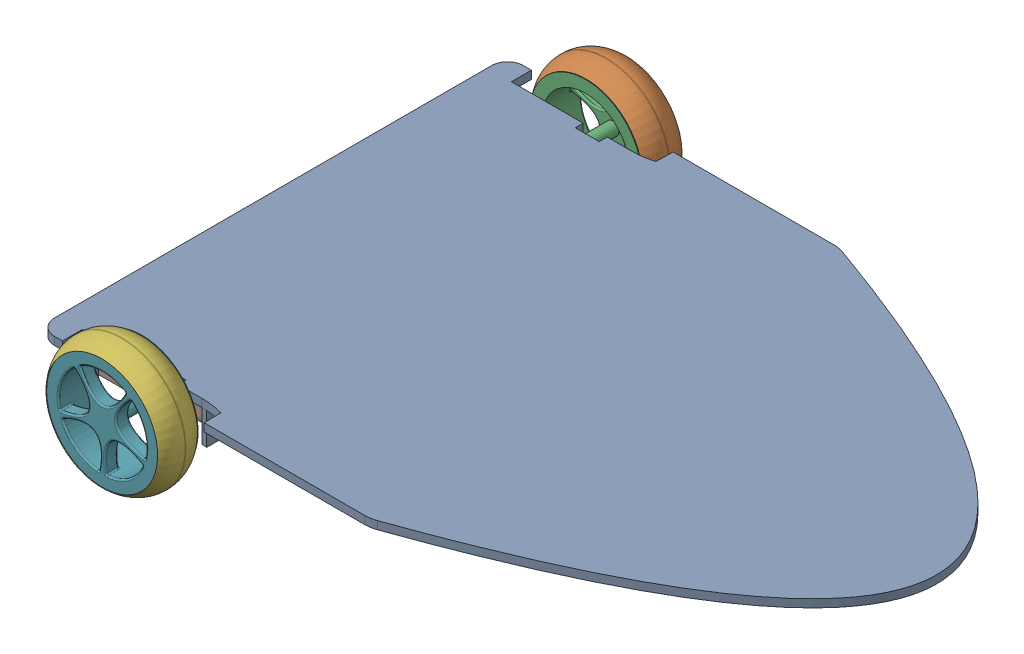
SolidWorks assembly Three_wheeled_base, configuration Predeterminado. Lengths in mm.
Overall size (832 160.33 657.43).
7 component instances, 5 part files, 12 mates.
Components (placement in the parent):
- Base-1: Base [Predeterminado] at (5.8411 10.0672 416) size (832 50 588)
- Rear_wheel-1: Rear_wheel [Predeterminado] at (-266.5903 -12.0958 99.7873) x (1 0 0) z (0 -1 0) size (160 66.79 160)
- Caster_coupler-1: Caster_coupler [Predeterminado] at (255.8411 5.8953 416) x (-1 0 0) z (0 0 1) size (37.38 89 35)
- Rear_coupler-1: Rear_coupler [Predeterminado] at (-286.1846 -2.1047 172.9246) x (1 0 0) z (0 0 -1) size (150 40 54)
- Rear_wheel-2: Rear_wheel [Predeterminado] at (-266.5903 -12.1135 732.213) x (1 0 0) z (0 1 0) size (160 66.79 160)
- Rear_coupler-2: Rear_coupler [Predeterminado] at (-286.1846 -22.1047 659.0757) size (150 40 54)
- Caster_wheel-2: Caster_wheel [Predeterminado] at (266.1413 -72.4241 416) x (1 0 0) z (0 -1 0) size (40 18 40)
Mates (geometry in assembly coordinates):
- Coincidente1: coincident anti-aligned: plane of Base-1 through (255.8411 3.8953 416) normal (0 1 0); plane of Caster_coupler-1 through (255.8411 3.8953 416) normal (0 -1 0)
- Concéntrica1: concentric aligned: circle of Base-1; circle of Caster_coupler-1
- Coincidente7: coincident anti-aligned: plane of Base-1 through (-200.5898 -32.1047 188.0801) normal (0 0 -1); plane of Coupler-1 through (-230.5898 -32.1047 188.0801) normal (0 0 1)
- Coincidente8: coincident anti-aligned: plane of Base-1 through (35.4102 7.8953 416.0001) normal (0 -1 0); plane of Coupler-1 through (-290.5898 7.8953 173.0801) normal (0 1 0)
- Coincidente9: coincident anti-aligned: plane of Base-1 through (-230.5898 7.8953 157.0601) normal (-1 0 0); plane of Coupler-1 through (-230.5898 -32.1047 158.0801) normal (1 0 0)
- Coincidente10: coincident anti-aligned: circle of Big_wheel-1; circle of Coupler-1
- Coincidente11: coincident anti-aligned: plane of Base-1 through (35.4102 7.8953 416.0001) normal (0 -1 0); plane of Coupler-2 through (-290.5898 7.8953 658.9201) normal (0 1 0)
- Coincidente12: coincident anti-aligned: plane of Base-1 through (-200.5898 -32.1047 643.9201) normal (0 0 1); plane of Coupler-2 through (-230.5898 7.8953 643.9201) normal (0 0 -1)
- Coincidente13: coincident anti-aligned: circle of Big_wheel-2; circle of Coupler-2
- Concéntrica2: concentric anti-aligned: cylinder of Caster_coupler-1 through (266.1413 -72.4241 398.5) axis (0 0 1) radius 2; axis of Small_wheel-2 through (266.1413 -72.4241 425) axis (0 0 -1)
- Distancia1: distance = 1 mm anti-aligned: plane of Small_wheel-2 through (266.1413 -72.4241 421) normal (0 0 1); plane of Caster_coupler-1 through (277.4494 -81.0324 422) normal (0 0 -1)
- Coincidente15: coincident anti-aligned: plane of Base-1 through (-230.5898 7.8953 674.9401) normal (-1 0 0); plane of Coupler-2 through (-230.5898 7.8953 673.9201) normal (1 0 0)
